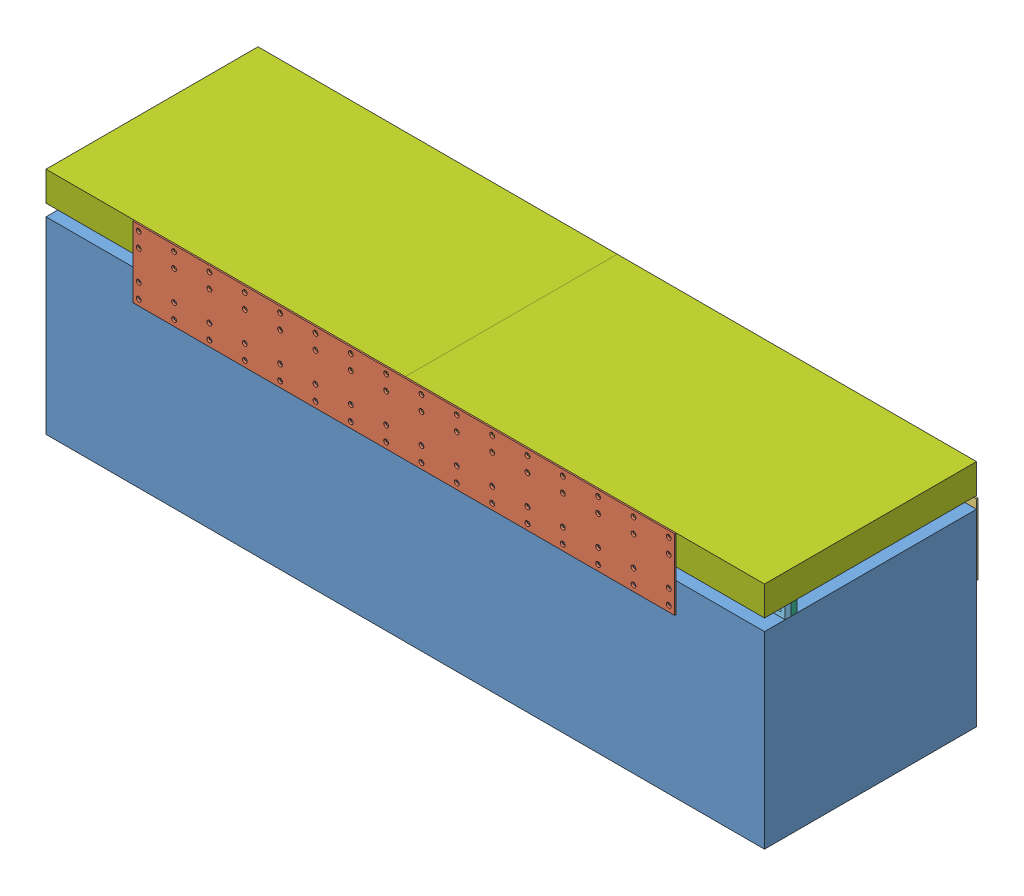
SolidWorks assembly Treadmill_Original, configuration Default. Lengths in mm.
Overall size (1549.4 495.3 463.55).
7 component instances, 7 part files, 21 mates.
Components (placement in the parent):
- Bottom Structure-1: Bottom Structure [Default] at (-1.3766 852.08 1423.4974) size (1549.4 406.4 457.2)
- Supporting Side Plate-1: Supporting Side Plate [Default] at (189.1234 788.58 1426.6724) size (1168.4 152.4 3.17)
- Supporting Bracket Front-1: Supporting Bracket Front [Default] at (1548.0234 718.73 963.1224) x (-1 0 0) z (0 0 -1) size (129.54 215.9 3.17)
- Supporting Bracket Rear-1: Supporting Bracket Rear [Default] at (-1.3766 718.73 963.1224) x (-1 0 0) z (0 0 -1) size (129.54 215.9 3.17)
- Supporting Sandwich Plate Bottom-2: Supporting Sandwich Plate Bottom [Default] at (-1.3766 852.08 1379.0474) size (1549.4 25.4 12.7)
- Supporting Sandwich Plate Top-1: Supporting Sandwich Plate Top [Default] at (-1.3766 852.08 1366.3474) size (1549.4 25.4 12.7)
- Top Structure-1: Top Structure [Default] at (-1.3766 877.48 1423.4974) size (1549.4 63.5 457.2)
Mates (geometry in assembly coordinates):
- Coincident1: coincident anti-aligned: plane of Bottom Structure-1 through (-1.3766 445.68 1423.4974) normal (0 0 1); plane of Supporting Side Plate-1 through (189.1234 788.58 1423.4974) normal (0 0 -1)
- Coincident12: coincident anti-aligned: plane of Bottom Structure-1 through (-1.3766 445.68 966.2974) normal (0 0 -1); plane of Supporting Bracket Front-1 through (1541.6734 877.48 966.2974) normal (0 0 1)
- Coincident17: coincident anti-aligned: plane of Bottom Structure-1 through (-1.3766 445.68 966.2974) normal (0 0 -1); plane of Supporting Bracket Rear-1 through (4.9734 877.48 966.2974) normal (0 0 1)
- Coincident27: coincident anti-aligned: plane of Bottom Structure-1 through (-1.3766 852.08 1423.4974) normal (0 1 0); plane of Supporting Sandwich Plate Bottom-2 through (-1.3766 852.08 1366.3474) normal (0 -1 0)
- Coincident31: coincident aligned: axis of Supporting Sandwich Plate Bottom-2 through (11.3234 864.78 1366.3474) axis (0 0 1); axis of Supporting Sandwich Plate Top-1 through (11.3234 864.78 1353.6474) axis (0 0 1)
- Coincident32: coincident aligned: axis of Supporting Sandwich Plate Bottom-2 through (1536.0854 864.78 1366.3474) axis (0 0 1); axis of Supporting Sandwich Plate Top-1 through (1536.0854 864.78 1353.6474) axis (0 0 1)
- Coincident33: coincident anti-aligned: plane of Supporting Sandwich Plate Bottom-2 through (-1.3766 852.08 1366.3474) normal (0 0 -1); plane of Supporting Sandwich Plate Top-1 through (-1.3766 852.08 1366.3474) normal (0 0 1)
- Coincident34: coincident anti-aligned: plane of Supporting Sandwich Plate Top-1 through (-1.3766 877.48 1353.6474) normal (0 1 0); plane of Top Structure-1 through (-1.3766 877.48 966.2974) normal (0 -1 0)
- Coincident36: coincident anti-aligned: plane of Supporting Side Plate-1 through (189.1234 788.58 1423.4974) normal (0 0 -1); plane of Top Structure-1 through (-1.3766 877.48 1423.4974) normal (0 0 1)
- Coincident37: coincident anti-aligned: plane of Supporting Bracket Front-1 through (1541.6734 877.48 966.2974) normal (0 0 1); plane of Top Structure-1 through (-1.3766 877.48 966.2974) normal (0 0 -1)
- Coincident38: coincident anti-aligned: plane of Supporting Bracket Rear-1 through (4.9734 877.48 966.2974) normal (0 0 1); plane of Top Structure-1 through (-1.3766 877.48 966.2974) normal (0 0 -1)
- Coincident39: coincident aligned: plane of Bottom Structure-1 through (1548.0234 445.68 1423.4974) normal (1 0 0); plane of Top Structure-1 through (1548.0234 877.48 966.2974) normal (1 0 0)
- Coincident40: coincident aligned: plane of Bottom Structure-1 through (1548.0234 445.68 1423.4974) normal (1 0 0); plane of Supporting Sandwich Plate Bottom-2 through (1548.0234 852.08 1366.3474) normal (1 0 0)
- Distance1: distance = 44.45 mm aligned: plane of Supporting Sandwich Plate Bottom-2 through (-1.3766 852.08 1379.0474) normal (0 0 1); plane of Bottom Structure-1 through (-1.3766 445.68 1423.4974) normal (0 0 1)
- Coincident42: coincident aligned: plane of Bottom Structure-1 through (-1.3766 445.68 1423.4974) normal (-1 0 0); plane of Supporting Bracket Rear-1 through (-1.3766 718.73 966.2974) normal (-1 0 0)
- Coincident43: coincident anti-aligned: plane of Supporting Bracket Rear-1 through (4.9734 877.48 966.2974) normal (0 0 1); plane of Top Structure-1 through (-1.3766 877.48 966.2974) normal (0 0 -1)
- Distance3: distance = 6.35 mm aligned: plane of Supporting Bracket Rear-1 through (11.3234 934.63 966.2974) normal (0 1 0); plane of Top Structure-1 through (-1.3766 940.98 966.2974) normal (0 1 0)
- Coincident45: coincident aligned: plane of Bottom Structure-1 through (1548.0234 445.68 1423.4974) normal (1 0 0); plane of Supporting Bracket Front-1 through (1548.0234 718.73 966.2974) normal (1 0 0)
- Distance4: distance = 6.35 mm aligned: plane of Supporting Bracket Front-1 through (1535.3234 934.63 966.2974) normal (0 1 0); plane of Top Structure-1 through (-1.3766 940.98 966.2974) normal (0 1 0)
- Coincident47: coincident aligned: plane of Supporting Side Plate-1 through (189.1234 940.98 1423.4974) normal (0 1 0); plane of Top Structure-1 through (-1.3766 940.98 966.2974) normal (0 1 0)
- Distance5: distance = 190.5 mm aligned: plane of Bottom Structure-1 through (1548.0234 445.68 1423.4974) normal (1 0 0); plane of Supporting Side Plate-1 through (1357.5234 788.58 1423.4974) normal (1 0 0)
